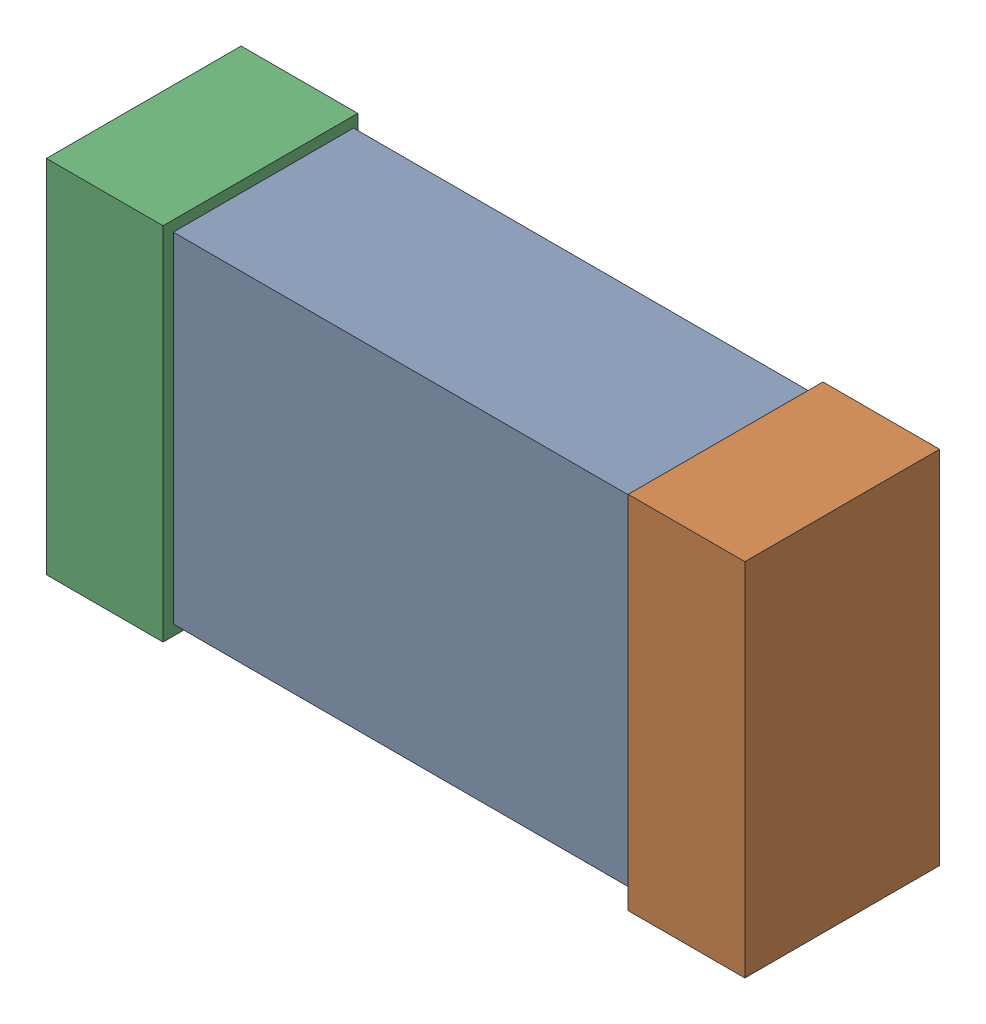
SolidWorks assembly R16, configuration Default. Lengths in mm.
Overall size (1.65 0.85 0.46).
6 component instances, 2 part files, 0 mates.
Components (placement in the parent):
- 432120720_19-1: 432120720_19 [Default] at (48.1003 17.2338 -0.8615) size (1.5 0.8 0.42)
  - Extruded (12)-1: Extruded (12) [Default] at origin size (1.5 0.8 0.42)
- 432120464_40-1: 432120464_40 [Default] at (48.7861 17.2338 -0.8715) size (0.28 0.85 0.46)
  - Extruded (11)-1: Extruded (11) [Default] at origin size (0.28 0.85 0.46)
- 432120464_41-1: 432120464_41 [Default] at (47.4146 17.2338 -0.8715) size (0.28 0.85 0.46)
  - Extruded (11)-1: Extruded (11) [Default] at origin size (0.28 0.85 0.46)
